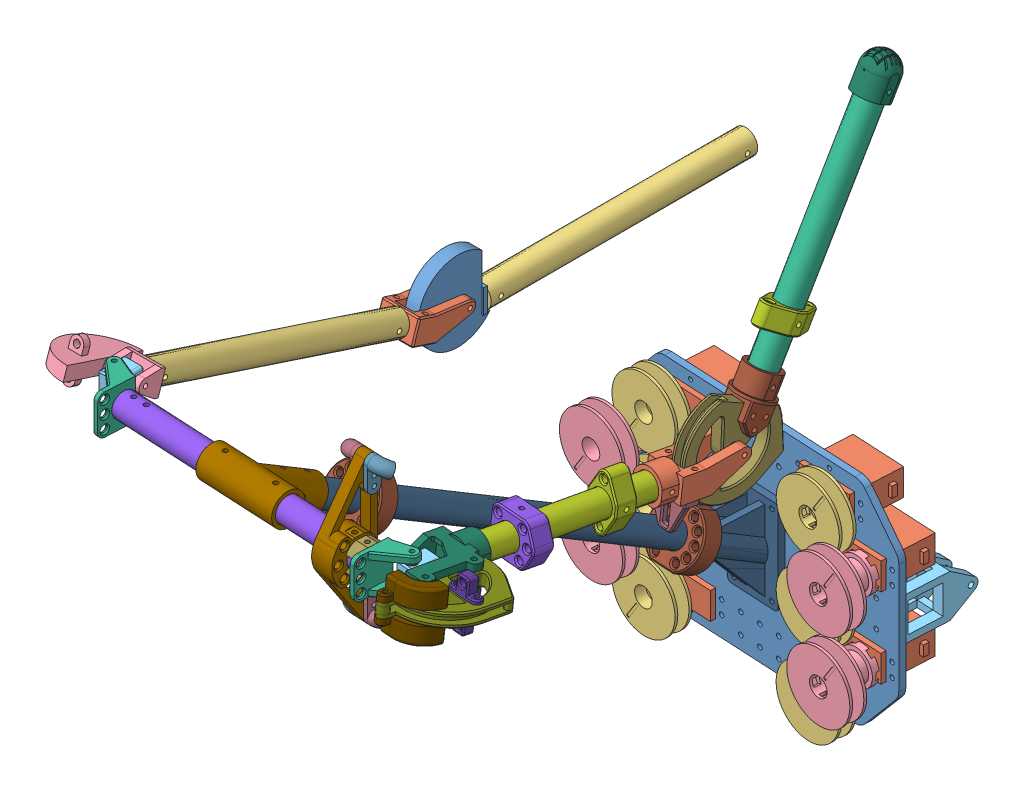
SolidWorks assembly leg, configuration ﾃﾞﾌｫﾙﾄ. Lengths in mm.
Overall size (337.74 498.67 533).
81 component instances, 34 part files, 137 mates.
Components (placement in the parent):
- knee1-1: knee1 [ﾃﾞﾌｫﾙﾄ] at origin size (12.5 60 66)
- knee2-1: knee2 [ﾃﾞﾌｫﾙﾄ] at (0 17.6456 91.0568) x (-1 0 0) z (0 -0.312628 -0.949876) size (28.5 23 60)
- pipe-1: pipe [ﾃﾞﾌｫﾙﾄ] at (0 75.4818 266.7838) x (-1 0 0) z (0 -0.312628 -0.949876) size (18 18 200)
- pipe-2: pipe [ﾃﾞﾌｫﾙﾄ] at (0 0 -185) size (18 18 200)
- shoulder1-1: shoulder1 [ﾃﾞﾌｫﾙﾄ] at (0 70.7924 252.5357) x (1 0 0) z (0 0.312628 0.949876) size (57 30 63)
- shoulder2-1: shoulder2 [ﾃﾞﾌｫﾙﾄ] at (0 79.5426 274.1322) x (1 0 0) z (0 0.000663 1) size (15 15 20)
- shoulder3-2: shoulder3 [ﾃﾞﾌｫﾙﾄ] at (32.4982 79.5596 299.803) x (0 1 -0.000663) z (-0.998699 -0.000034 -0.050986) size (29.5 33 38)
- wire_end_small-1: wire_end_small [ﾃﾞﾌｫﾙﾄ] at (256.2577 129.0444 42.6835) x (-0.071528 0.462872 0.883535) z (-0.03729 -0.886425 0.461367) size (40.5 24.5 15)
- wire_end_5_small-2: wire_end_5_small [ﾃﾞﾌｫﾙﾄ] at (241.707 71.9206 226.8576) x (0.00942 0.993081 -0.117057) z (0.080112 -0.117436 -0.989844) size (31 35.94 15)
- wire_root_curve-1: wire_root_curve [ﾃﾞﾌｫﾙﾄ] at (187.796 79.5649 307.7313) x (0 1 -0.000663) z (0.998699 0.000034 0.050986) size (110 40 16)
- wire_end_small-2: wire_end_small [ﾃﾞﾌｫﾙﾄ] at (246.9143 64.2873 162.5178) x (-0.00942 -0.993081 0.117057) z (-0.080112 0.117436 0.989844) size (40.5 24.5 15)
- connector_45-1: connector_45 [ﾃﾞﾌｫﾙﾄ] at (135.712 -128.1754 -54.6586) x (0.998699 0.000034 0.050986) z (-0.050986 0.000662 0.998699) size (40 70.39 54.3)
- knee-1: knee [ﾃﾞﾌｫﾙﾄ] at (254.5796 89.1552 63.445) x (0.996741 0.000053 0.080664) z (-0.03729 -0.886425 0.461367) size (28.65 93.18 98.72) (flexible)
  - knee_joint_connector-1: knee_joint_connector [outer] at origin size (28.1 28.1 37.95)
  - knee_joint_circle-1: knee_joint_circle [ﾃﾞﾌｫﾙﾄ] at (-4.65 5 31.1808) x (0 1 0) z (1 0 0) size (75 60.98 10)
  - knee2-1: knee2 [outer] at (0.35 53.2056 59.149) x (-1 0 0) z (0 -0.934649 -0.355571) size (28.5 25.58 60)
  - knee_support-1: knee_support [ﾃﾞﾌｫﾙﾄ] at (0.35 28.5085 59.3827) x (-1 0 0) z (0 -0.355571 0.934649) size (28.5 11 23)
  - bearing-1: bearing [ﾃﾞﾌｫﾙﾄ] at (6.1 5 31.1808) x (0 0.527519 -0.849543) z (0 0.849543 0.527519) size (7 5 7)
  - bearing-2: bearing [ﾃﾞﾌｫﾙﾄ] at (-5.4 5 31.1808) x (0 -0.208274 -0.978071) z (0 -0.978071 0.208274) size (7 5 7)
- shoulder-1: shoulder [ﾃﾞﾌｫﾙﾄ] at (238.1019 77.2052 271.4006) x (0.996741 0.000053 0.080664) z (-0.080112 0.117436 0.989844) size (88.08 36.85 85.64) (flexible)
  - shoulder_joint_connector-1: shoulder_joint_connector [outer] at origin size (39.7 24.5 59)
  - shoulder_joint_circle-1: shoulder_joint_circle [ﾃﾞﾌｫﾙﾄ] at (19.95 4.65 26) x (1 0 0) z (0 -1 0) size (40 79.64 10)
  - shoulder_fromknee_middle-2: shoulder_fromknee_middle [ﾃﾞﾌｫﾙﾄ] at (38.95 -5.35 26) x (1 0 0) z (0 1 0) size (24 8 13)
  - shoulder_fromknee_middle-3: shoulder_fromknee_middle [ﾃﾞﾌｫﾙﾄ] at (38.95 4.65 26) x (1 0 0) z (0 -1 0) size (24 8 13)
  - shoulder_fromknee_middle_curve-4: shoulder_fromknee_middle_curve [ﾃﾞﾌｫﾙﾄ] at (18.95 -5.35 58.641) x (0 0 1) z (0 1 0) size (28 28.97 13)
  - shoulder2-1: shoulder2 [ﾃﾞﾌｫﾙﾄ] at (0 0.5839 15.0342) x (1 0 0) z (0 -0.116779 0.993158) size (15 15 20)
  - shoulder3-1: shoulder3 [ﾃﾞﾌｫﾙﾄ] at (-32.7177 -2.3329 39.8407) x (0 -0.993158 -0.116779) z (0.999558 0.003473 -0.029536) size (29.5 33 38)
  - bearing-1: bearing [ﾃﾞﾌｫﾙﾄ] at (-8.25 0 20) x (0 -0.574007 -0.81885) z (0 -0.81885 0.574007) size (7 5 7)
  - bearing-2: bearing [ﾃﾞﾌｫﾙﾄ] at (8.25 0 20) x (0 0.990184 0.139771) z (0 -0.139771 0.990184) size (7 5 7)
  - bearing-3: bearing [ﾃﾞﾌｫﾙﾄ] at (0 -9.3613 28.9682) x (0.861407 0.059314 -0.504441) z (0.507916 -0.100594 0.855513) size (7 5 7)
  - bearing-4: bearing [ﾃﾞﾌｫﾙﾄ] at (0 7.0258 30.895) x (-0.933998 0.041723 -0.354835) z (-0.35728 -0.109071 0.927607) size (7 5 7)
  - shoulder_fromknee_middle_curve-5: shoulder_fromknee_middle_curve [mirror] at (18.95 4.65 58.641) x (0 0 1) z (0 1 0) size (28 28.97 13)
- base_motor-1: base_motor [ﾃﾞﾌｫﾙﾄ] at (111.2544 -128.1829 -65.9202) x (0 1 -0.000663) z (0.998699 0.000034 0.050986) size (192.73 114.3 257.01)
  - base-1: base [ﾃﾞﾌｫﾙﾄ] at origin size (160.1 5 220.2)
  - motor-1: motor [ﾃﾞﾌｫﾙﾄ] at (0 -30 -30.05) x (0 0 1) z (-1 0 0) size (73.36 59.5 70.97)
    - FB5311M-1: FB5311M [ﾃﾞﾌｫﾙﾄ] at origin size (54 44.25 20.1)
    - servo_horn_short-1: servo_horn_short [ﾃﾞﾌｫﾙﾄ] at (-10 42.5 0) x (-0.837169 0 -0.546944) z (0 1 0) size (50 57.04 17)
  - motor-2: motor [ﾃﾞﾌｫﾙﾄ] at (-60 -30 -30.05) x (0 0 1) z (-1 0 0) size (73.36 59.5 70.97)
    - FB5311M-1: FB5311M [ﾃﾞﾌｫﾙﾄ] at origin size (54 44.25 20.1)
    - servo_horn_short-1: servo_horn_short [ﾃﾞﾌｫﾙﾄ] at (-10 42.5 0) x (-0.837169 0 -0.546944) z (0 1 0) size (50 57.04 17)
  - motor-3: motor [ﾃﾞﾌｫﾙﾄ] at (60 -30 -30.05) x (0 0 1) z (-1 0 0) size (73.36 59.5 70.97)
    - FB5311M-1: FB5311M [ﾃﾞﾌｫﾙﾄ] at origin size (54 44.25 20.1)
    - servo_horn_short-1: servo_horn_short [ﾃﾞﾌｫﾙﾄ] at (-10 42.5 0) x (-0.837169 0 -0.546944) z (0 1 0) size (50 57.04 17)
  - motor_long-6: motor_long [ﾃﾞﾌｫﾙﾄ] at (-30 -30 -55.05) x (0 0 1) z (-1 0 0) size (73.92 74.5 73.92) (flexible)
    - FB5311M-1: FB5311M [ﾃﾞﾌｫﾙﾄ] at origin size (54 44.25 20.1)
    - servo_horn_long-1: servo_horn_long [ﾃﾞﾌｫﾙﾄ] at (-10 42.5 0) x (0.789041 0 0.61434) z (0 1 0) size (50 57.04 32)
  - motor_long-5: motor_long [ﾃﾞﾌｫﾙﾄ] at (30 -30 -55.05) x (0 0 1) z (-1 0 0) size (75.45 74.5 73.44)
    - FB5311M-1: FB5311M [ﾃﾞﾌｫﾙﾄ] at origin size (54 44.25 20.1)
    - servo_horn_long-1: servo_horn_long [ﾃﾞﾌｫﾙﾄ] at (-10 42.5 0) x (-0.837169 0 -0.546944) z (0 1 0) size (50 57.04 32)
  - wheel_support-1: wheel_support [ﾃﾞﾌｫﾙﾄ] at (0 0 -67.1) x (0 0 1) z (0 -1 0) size (28.5 32 55)
  - connector_45-1: connector_45 [ﾃﾞﾌｫﾙﾄ] at (0 10 25) x (0 0 1) z (0 1 0) size (40 70.39 54.3)
  - motor-4: motor [ﾃﾞﾌｫﾙﾄ] at (-60 -30 80.05) x (0 0 -1) z (1 0 0) size (73.36 59.5 70.97)
    - FB5311M-1: FB5311M [ﾃﾞﾌｫﾙﾄ] at origin size (54 44.25 20.1)
    - servo_horn_short-1: servo_horn_short [ﾃﾞﾌｫﾙﾄ] at (-10 42.5 0) x (-0.837169 0 -0.546944) z (0 1 0) size (50 57.04 17)
  - motor-5: motor [ﾃﾞﾌｫﾙﾄ] at (0 -30 80.05) x (0 0 -1) z (1 0 0) size (73.36 59.5 70.97)
    - FB5311M-1: FB5311M [ﾃﾞﾌｫﾙﾄ] at origin size (54 44.25 20.1)
    - servo_horn_short-1: servo_horn_short [ﾃﾞﾌｫﾙﾄ] at (-10 42.5 0) x (-0.837169 0 -0.546944) z (0 1 0) size (50 57.04 17)
  - motor-6: motor [ﾃﾞﾌｫﾙﾄ] at (60 -30 80.05) x (0 0 -1) z (1 0 0) size (73.36 59.5 70.97)
    - FB5311M-1: FB5311M [ﾃﾞﾌｫﾙﾄ] at origin size (54 44.25 20.1)
    - servo_horn_short-1: servo_horn_short [ﾃﾞﾌｫﾙﾄ] at (-10 42.5 0) x (-0.837169 0 -0.546944) z (0 1 0) size (50 57.04 17)
  - motor_long-7: motor_long [ﾃﾞﾌｫﾙﾄ] at (-30 -30 105.05) x (0 0 -1) z (1 0 0) size (75.45 74.5 73.44)
    - FB5311M-1: FB5311M [ﾃﾞﾌｫﾙﾄ] at origin size (54 44.25 20.1)
    - servo_horn_long-1: servo_horn_long [ﾃﾞﾌｫﾙﾄ] at (-10 42.5 0) x (-0.837169 0 -0.546944) z (0 1 0) size (50 57.04 32)
  - motor_long-8: motor_long [ﾃﾞﾌｫﾙﾄ] at (30 -30 105.05) x (0 0 -1) z (1 0 0) size (75.45 74.5 73.44)
    - FB5311M-1: FB5311M [ﾃﾞﾌｫﾙﾄ] at origin size (54 44.25 20.1)
    - servo_horn_long-1: servo_horn_long [ﾃﾞﾌｫﾙﾄ] at (-10 42.5 0) x (-0.837169 0 -0.546944) z (0 1 0) size (50 57.04 32)
  - wheel_support-2: wheel_support [ﾃﾞﾌｫﾙﾄ] at (0 0 117.1) x (0 0 -1) z (0 -1 0) size (28.5 32 55)
- pipe_foot-1: pipe_foot [ﾃﾞﾌｫﾙﾄ] at (254.5796 89.1552 63.445) x (-0.996741 -0.000053 -0.080664) z (0.03729 0.886425 -0.461367) size (18 18 190)
- pipe_leg-1: pipe_leg [ﾃﾞﾌｫﾙﾄ] at (238.1019 77.2052 271.4006) x (0.996741 0.000053 0.080664) z (0.080112 -0.117436 -0.989844) size (18 18 150)
- pipe_shoulder-1: pipe_shoulder [ﾃﾞﾌｫﾙﾄ] at (17.5177 79.5591 299.0382) x (0 1 -0.000663) z (0.998699 0.000034 0.050986) size (18 18 200)
- connector_T-2: connector_T [ﾃﾞﾌｫﾙﾄ] at (117.3877 79.5625 304.1368) x (0.044155 -0.500573 -0.864567) z (-0.025493 -0.865694 0.499924) size (62 60 24)
- pipe_body-1: pipe_body [body] at (117.8292 74.5568 295.4912) x (-0.025493 -0.865694 0.499924) z (0.044155 -0.500573 -0.864567) size (18 18 400)
- wire_from_base_mini-1: wire_from_base_mini [ﾃﾞﾌｫﾙﾄ] at (133.5043 -103.1468 -11.4302) x (0.998699 0.000034 0.050986) z (-0.044155 0.500573 0.864567) size (42.5 38.28 15)
- wire_from_base_mini-2: wire_from_base_mini [ﾃﾞﾌｫﾙﾄ] at (121.6928 30.7566 219.8415) x (0.998699 0.000034 0.050986) z (-0.044155 0.500573 0.864567) size (42.5 38.28 15)
- shoulder_patch-1: shoulder_patch [ﾃﾞﾌｫﾙﾄ] at (204.7738 79.5655 308.5981) x (0 1 -0.000663) z (0.998699 0.000034 0.050986) size (23.48 22.98 10)
- wire_root_curve_support-1: wire_root_curve_support [ﾃﾞﾌｫﾙﾄ] at (199.5464 29.5553 293.3448) x (0 1 -0.000663) z (0.998699 0.000034 0.050986) size (25 12.64 15.99)
- wire_root_curve_support_mirror-1: wire_root_curve_support_mirror [ﾃﾞﾌｫﾙﾄ] at (193.5542 129.5551 292.9726) x (0 -1 0.000663) z (-0.998699 -0.000034 -0.050986) size (25 12.64 15.99)
- wire_root_curve_support_mirror-2: wire_root_curve_support_mirror [45] at (191.5568 29.5551 292.937) x (0 1 -0.000663) z (0.998699 0.000034 0.050986) size (25 12.5 15.99)
- wire_root_curve_support-2: wire_root_curve_support [76] at (185.5646 129.5549 292.5647) x (0 -1 0.000663) z (-0.998699 -0.000034 -0.050986) size (25 12.37 15.99)
- foot_simple-1: foot_simple [ﾃﾞﾌｫﾙﾄ] at (261.6647 257.576 -24.2147) x (0.996741 0.000053 0.080664) z (-0.071528 0.462872 0.883535) size (23.48 27.23 24.5)
- wheel-1: wheel [ﾃﾞﾌｫﾙﾄ] at (46.7909 -128.2183 -119.2763) x (0.050879 0.063944 -0.996656) z (0.998699 0.000034 0.050986) size (27.11 27.11 8)
Mates (geometry in assembly coordinates):
- 同心円2: concentric aligned: cylinder of knee2-1 through (0 12.9562 76.8087) axis (0 0.312628 0.949876) radius 6.325; cylinder of pipe-1 through (0 12.9562 76.8087) axis (0 0.312628 0.949876) radius 6.25
- 一致1: coincident anti-aligned: plane of knee2-1 through (0 12.9562 76.8087) normal (0 0.312628 0.949876); plane of pipe-1 through (0 12.9562 76.8087) normal (0 -0.312628 -0.949876)
- 同心円3: concentric aligned: cylinder of knee1-1 through (0 0 15) axis (0 0 -1) radius 6.25; cylinder of pipe-2 through (0 0 15) axis (0 0 -1) radius 6.25
- 一致2: coincident anti-aligned: plane of knee1-1 through (0 0 15) normal (0 0 -1); plane of pipe-2 through (0 0 15) normal (0 0 1)
- 一致3: coincident aligned: plane of knee2-1 through (0 17.6456 91.0568) normal (0 0.949876 -0.312628); plane of pipe-1 through (0 75.4818 266.7838) normal (0 0.949876 -0.312628)
- 一致4: coincident aligned: plane of knee1-1 through (0 0 0) normal (0 1 0); plane of pipe-2 through (0 0 -185) normal (0 1 0)
- 幅2: width anti-aligned: plane of knee2-1 through (-7.25 9 36) normal (1 0 0); plane of knee1-1 through (7.25 9 36) normal (-1 0 0); plane of knee2-1 through (-5 9 36) normal (-1 0 0); plane of knee1-1 through (5 9 36) normal (1 0 0)
- 同心円6: concentric anti-aligned: cylinder of shoulder2-1 through (0 72.0526 289.1372) axis (0 1 -0.000663) radius 2.45; cylinder of shoulder3-2 through (0 69.8026 289.1387) axis (0 -1 0.000663) radius 1.65
- 幅4: width aligned: plane of shoulder3-2 through (0 69.8026 289.1387) normal (0 1 -0.000663); plane of shoulder2-1 through (0 89.3026 289.1257) normal (0 -1 0.000663); plane of shoulder3-2 through (-7.5 72.0559 294.1372) normal (0 -1 0.000663); plane of shoulder2-1 through (-7.5 87.0559 294.1272) normal (0 1 -0.000663)
- 同心円7: concentric aligned: cylinder of shoulder3-2 through (17.5177 79.5591 299.0382) axis (0.998699 0.000034 0.050986) radius 6.45; cylinder of pipe-3 through (17.1329 100.1519 293.0392) axis (0.996076 0.003559 0.08843) radius 6.25
- 一致7: coincident anti-aligned: plane of shoulder3-2 through (17.5177 79.5591 299.0382) normal (0.998699 0.000034 0.050986); plane of pipe-3 through (17.1329 100.1519 293.0392) normal (-0.996076 -0.003559 -0.08843)
- 一致8: coincident anti-aligned: plane of shoulder3-2 through (32.4982 79.5596 299.803) normal (0.050986 -0.000662 -0.998699); plane of pipe-3 through (216.3481 100.8637 310.7252) normal (-0.088502 0.040056 0.99527)
- 同心円8: concentric anti-aligned: cylinder of pipe-4 through (270.6476 122.5449 77.128) axis (-0.154661 -0.093841 0.983501) radius 6.25; cylinder of shoulder1-3 through (228.7413 175.6864 165.6652) axis (-0.138361 -0.342084 -0.929427) radius 6.25
- 同心円9: concentric anti-aligned: cylinder of knee2-2 through (196.4818 175.5319 -79.2352) axis (0.987757 -0.006404 -0.155872) radius 1.65; cylinder of knee1-2 through (228.292 123.8982 -68.5769) axis (-0.99942 0.001398 0.03403) radius 1.65
- 同心円10: concentric aligned: cylinder of shoulder1-3 through (238.9499 180.0829 176.5145) axis (0.9894 -0.005962 -0.145095) radius 1.65; cylinder of shoulder2-2 through (225.1612 174.2633 198.3122) axis (0.987981 -0.006346 -0.154447) radius 2.25
- 一致9: coincident anti-aligned: plane of pipe-4 through (239.7153 103.7767 273.8281) normal (-0.01468 0.995587 0.092686); plane of shoulder1-3 through (226.6659 170.5552 151.7238) normal (0.044094 -0.939651 0.339282)
- 同心円11: concentric aligned: cylinder of pipe-4 through (270.6476 122.5449 77.128) axis (-0.154661 -0.093841 0.983501) radius 6.25; cylinder of knee2-2 through (196.3165 168.6457 -38.2986) axis (0.155994 0.051502 0.986414) radius 6.5
- 同心円12: concentric aligned: cylinder of pipe-5 through (281.7295 136.6436 7.4767) axis (0.159061 0.201035 -0.966584) radius 6.25; cylinder of knee1-2 through (222.6082 133.8129 -88.9826) axis (-0.021318 0.753541 -0.657055) radius 6.25
- 一致10: coincident anti-aligned: plane of pipe-4 through (239.7153 103.7767 273.8281) normal (-0.154661 -0.093841 0.983501); plane of shoulder1-3 through (228.7413 175.6864 165.6652) normal (-0.138361 -0.342084 -0.929427)
- 一致11: coincident anti-aligned: plane of pipe-4 through (270.6476 122.5449 77.128) normal (0.154661 0.093841 -0.983501); plane of knee2-2 through (196.3165 168.6457 -38.2986) normal (0.155994 0.051502 0.986414)
- 一致12: coincident anti-aligned: plane of pipe-5 through (281.7295 136.6436 7.4767) normal (-0.159061 -0.201035 0.966584); plane of knee1-2 through (222.6082 133.8129 -88.9826) normal (-0.021318 0.753541 -0.657055)
- 一致13: coincident aligned: plane of pipe-4 through (239.7153 103.7767 273.8281) normal (-0.01468 0.995587 0.092686); plane of knee2-2 through (198.6564 169.4182 -23.5024) normal (-0.00171 0.998652 -0.05187)
- 幅5: width anti-aligned: plane of knee2-2 through (183.6409 175.6151 -77.2088) normal (0.987757 -0.006404 -0.155872); plane of knee1-2 through (196.4818 175.5319 -79.2352) normal (-0.987757 0.006404 0.155872); plane of knee2-2 through (218.2978 123.9121 -68.2366) normal (-0.99942 0.001398 0.03403); plane of knee1-2 through (228.292 123.8982 -68.5769) normal (0.99942 -0.001398 -0.03403)
- 幅6: width anti-aligned: plane of shoulder1-3 through (238.9499 180.0829 176.5145) normal (-0.9894 0.005962 0.145095); plane of shoulder2-2 through (222.1301 180.1842 178.9811) normal (0.9894 -0.005962 -0.145095); plane of shoulder1-3 through (242.2996 182.2702 210.4948) normal (0.987981 -0.006346 -0.154447); plane of shoulder2-2 through (227.4799 182.3654 212.8115) normal (-0.987981 0.006346 0.154447)
- 一致14: coincident aligned: plane of pipe-5 through (313.5418 176.8507 -185.8401) normal (0.031919 0.977489 0.208556); plane of knee1-2 through (222.2884 145.116 -98.8384) normal (0.026562 0.6574 0.753074)
- 同心円13: concentric anti-aligned: cylinder of pipe-3 through (17.1329 100.1519 293.0392) axis (0.996076 0.003559 0.08843) radius 6.25; cylinder of shoulder3-3 through (217.3952 175.081 218.2134) axis (-0.992021 0.005176 0.125969) radius 6.25
- 一致15: coincident anti-aligned: plane of pipe-3 through (216.3481 100.8637 310.7252) normal (-0.088502 0.040056 0.99527); plane of shoulder3-3 through (202.5149 175.1586 220.103) normal (-0.126075 -0.040725 -0.991184)
- 一致16: coincident anti-aligned: plane of pipe-3 through (216.3481 100.8637 310.7252) normal (0.996076 0.003559 0.08843); plane of shoulder3-3 through (217.3952 175.081 218.2134) normal (-0.992021 0.005176 0.125969)
- 同心円14: concentric aligned: cylinder of shoulder2-2 through (234.1169 167.1276 207.3332) axis (0 0.999157 -0.041052) radius 2.25; cylinder of shoulder3-3 through (234.1169 184.3631 206.6251) axis (0 0.999157 -0.041052) radius 1.65
- 幅7: width anti-aligned: plane of shoulder3-3 through (234.1169 184.3631 206.6251) normal (0 -0.999157 0.041052); plane of shoulder2-2 through (234.1169 164.8795 207.4256) normal (0 0.999157 -0.041052); plane of shoulder3-3 through (227.4799 182.3654 212.8115) normal (0 0.999157 -0.041052); plane of shoulder2-2 through (227.4799 167.378 213.4273) normal (0 -0.999157 0.041052)
- 同心円15: concentric anti-aligned: cylinder of knee1-1 through (5 9 36) axis (-1 0 0) radius 1.65; cylinder of knee2-1 through (7.25 9 36) axis (1 0 0) radius 1.65
- 同心円16: concentric anti-aligned: cylinder of pipe-1 through (0 12.9562 76.8087) axis (0 0.312628 0.949876) radius 6.25; cylinder of shoulder1-1 through (0 75.4818 266.7838) axis (0 -0.312628 -0.949876) radius 6.25
- 同心円17: concentric anti-aligned: cylinder of shoulder1-1 through (-8.5 79.5459 279.1322) axis (-1 0 0) radius 1.65; cylinder of shoulder2-1 through (-7.5 79.5459 279.1322) axis (1 0 0) radius 2.45
- 一致17: coincident anti-aligned: plane of pipe-1 through (0 75.4818 266.7838) normal (0 0.312628 0.949876); plane of shoulder1-1 through (0 75.4818 266.7838) normal (0 -0.312628 -0.949876)
- 幅8: width anti-aligned: plane of shoulder1-1 through (-8.5 79.5459 279.1322) normal (1 0 0); plane of shoulder2-1 through (8.5 79.5459 279.1322) normal (-1 0 0); plane of shoulder1-1 through (-7.5 87.0559 294.1272) normal (-1 0 0); plane of shoulder2-1 through (7.5 87.0559 294.1272) normal (1 0 0)
- 一致18: coincident aligned: plane of pipe-1 through (0 75.4818 266.7838) normal (0 0.949876 -0.312628); plane of shoulder1-1 through (0 70.7924 252.5357) normal (0 0.949876 -0.312628)
- 同心円21: concentric anti-aligned: cylinder of pipe-3 through (17.1329 100.1519 293.0392) axis (0.996076 0.003559 0.08843) radius 9; cylinder of wire_root_curve-1 through (195.7856 79.5652 308.1392) axis (-0.998699 -0.000034 -0.050986) radius 9.25
- 同心円22: concentric aligned: cylinder of pipe-3 through (17.1329 100.1519 293.0392) axis (0.996076 0.003559 0.08843) radius 9; cylinder of connector_T-1 through (86.8582 100.4011 299.2293) axis (0.996076 0.003559 0.08843) radius 9.25
- 同心円23: concentric anti-aligned: cylinder of connector_T-1 through (115.8191 108.7078 311.9303) axis (0.070862 -0.630668 -0.77281) radius 9.25; cylinder of pipe-6 through (136.2448 -134.2161 -65.0917) axis (-0.044155 0.500573 0.864567) radius 9
- 正接1: tangent anti-aligned: cylinder of connector_T-1 through (86.8582 100.4011 299.2293) axis (0.996076 0.003559 0.08843) radius 13; plane of pipe-6 through (118.5828 66.0133 280.7352) normal (-0.044155 0.500573 0.864567)
- 同心円25: concentric aligned: cylinder of pipe-6 through (136.2448 -134.2161 -65.0917) axis (-0.044155 0.500573 0.864567) radius 9; cylinder of wire_all-1 through (123.3985 11.4189 186.4422) axis (-0.044155 0.500573 0.864567) radius 9
- 同心円26: concentric aligned: cylinder of pipe-6 through (136.2448 -134.2161 -65.0917) axis (-0.044155 0.500573 0.864567) radius 9; cylinder of connector_45-1 through (136.6759 -139.103 -73.5322) axis (-0.044155 0.500573 0.864567) radius 9.4
- 一致23: coincident aligned: plane of pipe-6 through (118.5828 66.0133 280.7352) normal (0.982784 -0.133648 0.127573); plane of connector_45-1 through (135.712 -128.1754 -54.6586) normal (0.998699 0.000034 0.050986)
- 一致24: coincident anti-aligned: plane of connector_T-1 through (116.7405 100.5078 301.8822) normal (-0.996076 -0.003559 -0.08843); plane of pipe-6 through (118.5828 66.0133 280.7352) normal (0.982784 -0.133648 0.127573)
- 一致25: coincident anti-aligned: plane of connector_45-1 through (135.9669 -128.1788 -59.6521) normal (0.050986 -0.000662 -0.998699); plane of plate-1 through (65.1542 -294.6616 162.0898) normal (-0.119372 0.848521 -0.515521)
- 同心円27: concentric aligned: cylinder of connector_45-1 through (118.2178 -98.1433 -6.2051) axis (0.050986 -0.000662 -0.998699) radius 1.75; cylinder of plate-1 through (85.9891 -278.9347 183.151) axis (0.119372 -0.848521 0.515521) radius 1.75
- 同心円28: concentric aligned: cylinder of connector_45-1 through (118.2178 -158.1433 -6.1654) axis (0.050986 -0.000662 -0.998699) radius 1.75; cylinder of plate-1 through (73.4361 -310.6791 133.8082) axis (0.119372 -0.848521 0.515521) radius 1.75
- 同心円29: concentric aligned: cylinder of pipe-6 through (136.2448 -134.2161 -65.0917) axis (-0.044155 0.500573 0.864567) radius 9; cylinder of wire_all-2 through (130.6166 -70.4106 45.1102) axis (-0.044155 0.500573 0.864567) radius 9
- 同心円30: concentric aligned: cylinder of pipe-5 through (281.7295 136.6436 7.4767) axis (0.159061 0.201035 -0.966584) radius 9; cylinder of wire_end_small-1 through (255.978 122.3962 46.1438) axis (0.03729 0.886425 -0.461367) radius 9.25
- 一致26: coincident anti-aligned: plane of pipe-5 through (313.5418 176.8507 -185.8401) normal (0.986753 -0.064026 0.149064); plane of wire_end_small-1 through (256.2577 129.0444 42.6835) normal (-0.996741 -0.000053 -0.080664)
- 同心円31: concentric anti-aligned: cylinder of pipe-4 through (270.6476 122.5449 77.128) axis (-0.154661 -0.093841 0.983501) radius 9; cylinder of wire_end_small-2 through (246.3135 65.1681 169.9416) axis (0.080112 -0.117436 -0.989844) radius 9.25
- 一致27: coincident anti-aligned: plane of pipe-4 through (239.7153 103.7767 273.8281) normal (-0.987858 -0.000103 -0.155356); plane of wire_end_small-2 through (246.9143 64.2873 162.5178) normal (0.996741 0.000053 0.080664)
- 同心円32: concentric aligned: cylinder of pipe-4 through (270.6476 122.5449 77.128) axis (-0.154661 -0.093841 0.983501) radius 9; cylinder of wire_end_5_small-2 through (242.3079 71.0399 219.4338) axis (-0.080112 0.117436 0.989844) radius 9.25
- 一致28: coincident aligned: plane of pipe-4 through (239.7153 103.7767 273.8281) normal (-0.01468 0.995587 0.092686); plane of wire_end_5_small-2 through (241.707 71.9206 226.8576) normal (0.00942 0.993081 -0.117057)
- 幅9: width anti-aligned: plane of knee2-2 through (183.6409 175.6151 -77.2088) normal (0.987757 -0.006404 -0.155872); plane of knee-1/knee_joint_circle-1 through (196.4818 175.5319 -79.2352) normal (-0.987757 0.006404 0.155872); plane of knee2-2 through (248.4244 63.8299 81.8734) normal (-0.996741 -0.000053 -0.080664); plane of knee-1/knee_joint_circle-1 through (258.3918 63.8305 82.6801) normal (0.996741 0.000053 0.080664)
- 同心円35: concentric aligned: cylinder of pipe-4 through (270.6476 122.5449 77.128) axis (-0.154661 -0.093841 0.983501) radius 6.25; cylinder of shoulder-1/shoulder_joint_connector-1 through (237.7483 62.0339 260.918) axis (-0.044155 0.500573 0.864567) radius 6.325
- 一致31: coincident anti-aligned: plane of pipe-4 through (239.7153 103.7767 273.8281) normal (-0.154661 -0.093841 0.983501); plane of shoulder-1/shoulder_joint_connector-1 through (238.1019 77.2052 271.4006) normal (0.080112 -0.117436 -0.989844)
- 同心円36: concentric aligned: cylinder of shoulder2-2 through (225.1612 174.2633 198.3122) axis (0.987981 -0.006346 -0.154447) radius 2.25; cylinder of shoulder-1/shoulder_joint_connector-1 through (246.2179 79.5545 291.9839) axis (0.996741 0.000053 0.080664) radius 1.65
- 平行1: parallel anti-aligned: plane of pipe-4 through (239.7153 103.7767 273.8281) normal (-0.01468 0.995587 0.092686); plane of shoulder-1/shoulder_joint_circle-1 through (255.9478 84.8774 298.2015) normal (-0.00942 -0.993081 0.117057)
- 幅10: width anti-aligned: plane of shoulder-1/shoulder_joint_connector-1 through (247.8202 77.2057 272.1871) normal (-0.996741 -0.000053 -0.080664); plane of shoulder2-2 through (218.1836 135.3588 202.3528) normal (0.989315 -0.033774 -0.141829); plane of shoulder-1/shoulder_joint_connector-1 through (242.2996 182.2702 210.4948) normal (0.987981 -0.006346 -0.154447); plane of shoulder2-2 through (227.4799 182.3654 212.8115) normal (-0.987981 0.006346 0.154447)
- 同心円37: concentric aligned: cylinder of knee2-2 through (185.7003 159.3067 -44.2423) axis (-0.00171 0.998652 -0.05187) radius 1.75; cylinder of knee_support-1 through (185.7054 156.3107 -44.0867) axis (-0.00171 0.998652 -0.05187) radius 1.75
- 同心円38: concentric aligned: cylinder of knee2-2 through (204.4676 159.185 -47.2039) axis (-0.00171 0.998652 -0.05187) radius 1.75; cylinder of knee_support-1 through (204.4728 156.189 -47.0483) axis (-0.00171 0.998652 -0.05187) radius 1.75
- 一致32: coincident anti-aligned: plane of knee2-2 through (208.2109 159.4233 -42.7394) normal (0.00171 -0.998652 0.05187); plane of knee_support-1 through (195.084 159.2458 -45.7231) normal (-0.00171 0.998652 -0.05187)
- 同心円39: concentric: cylinder of pipe-5 through (185.2479 180.0429 -108.9085) axis (-0.146891 0.298304 -0.9431) radius 6.25; cylinder of knee-1/Assem1^knee-1/knee_joint_connector-1 through (183.0445 184.5175 -123.055) axis (0.146891 -0.298304 0.9431) radius 6.75
- 一致33: coincident: plane of pipe-5 through (185.2479 180.0429 -108.9085) normal (0.146891 -0.298304 0.9431); plane of knee-1/Assem1^knee-1/knee_joint_connector-1 through (185.2479 180.0429 -108.9085) normal (-0.146891 0.298304 -0.9431)
- 同心円40: concentric: cylinder of knee2-2 through (196.4818 175.5319 -79.2352) axis (0.987757 -0.006404 -0.155872) radius 1.65; cylinder of knee-1/Assem1^knee-1/knee_joint_circle-1 through (195.0001 175.5415 -79.0014) axis (-0.987757 0.006404 0.155872) radius 2.25
- 幅11: width: plane of knee2-2 through (183.6409 175.6151 -77.2088) normal (0.987757 -0.006404 -0.155872); plane of knee-1/Assem1^knee-1/knee_joint_circle-1 through (196.4818 175.5319 -79.2352) normal (-0.987757 0.006404 0.155872); plane of knee2-2 through (185.1226 175.6055 -77.4427) normal (-0.987757 0.006404 0.155872); plane of knee-1/Assem1^knee-1/knee_joint_circle-1 through (195.0001 175.5415 -79.0014) normal (0.987757 -0.006404 -0.155872)
- 同心円41: concentric anti-aligned: cylinder of pipe-5 through (281.7295 136.6436 7.4767) axis (0.159061 0.201035 -0.966584) radius 9; cylinder of knee-1/knee_joint_connector-1 through (247.6677 -27.845 59.8145) axis (-0.050678 0.110443 0.99259) radius 6.325
- 一致34: coincident anti-aligned: plane of pipe-5 through (281.7295 136.6436 7.4767) normal (-0.159061 -0.201035 0.966584); plane of knee-1/knee_joint_connector-1 through (254.5796 89.1552 63.445) normal (0.03729 0.886425 -0.461367)
- 同心円42: concentric aligned: cylinder of pipe-4 through (270.6476 122.5449 77.128) axis (-0.154661 -0.093841 0.983501) radius 6.25; cylinder of knee-1/knee2-1 through (243.7093 -5.5436 144.2014) axis (-0.044155 0.500573 0.864567) radius 6.325
- 一致35: coincident anti-aligned: plane of pipe-4 through (270.6476 122.5449 77.128) normal (0.154661 0.093841 -0.983501); plane of knee-1/knee2-1 through (250.1188 59.5899 122.924) normal (-0.080112 0.117436 0.989844)
- 一致36: coincident: plane of pipe-4 through (225.0662 136.8995 181.2502) normal (-0.989315 0.033774 0.141829); plane of knee-1 through (189.6272 188.6981 -78.2867) normal (0.989315 -0.033774 -0.141829)
- 同心円43: concentric anti-aligned: cylinder of pipe-3 through (17.1329 100.1519 293.0392) axis (0.996076 0.003559 0.08843) radius 6.25; cylinder of shoulder-1/shoulder3-1 through (217.2576 79.5659 309.2354) axis (-0.998699 -0.000034 -0.050986) radius 6.45
- 一致37: coincident anti-aligned: plane of pipe-3 through (216.3481 100.8637 310.7252) normal (0.996076 0.003559 0.08843); plane of shoulder-1/shoulder3-1 through (217.2576 79.5659 309.2354) normal (-0.998699 -0.000034 -0.050986)
- 同心円44: concentric aligned: cylinder of pipe-5 through (274.0417 138.7276 -1.1143) axis (0.986753 -0.064026 0.149064) radius 1.75; cylinder of knee-1/knee_joint_connector-1 through (236.9511 -27.017 66.7313) axis (0.998699 0.000034 0.050986) radius 1.65
- 幅12: width aligned: plane of pipe-3 through (216.3481 100.8637 310.7252) normal (0.996076 0.003559 0.08843); plane of pipe-3 through (17.1329 100.1519 293.0392) normal (-0.996076 -0.003559 -0.08843); plane of connector_T-1 through (146.6227 100.6146 304.5351) normal (0.996076 0.003559 0.08843); plane of connector_T-1 through (86.8582 100.4011 299.2293) normal (-0.996076 -0.003559 -0.08843)
- 同心円45: concentric anti-aligned: cylinder of connector_45-1 through (148.1788 -158.1423 -4.6358) axis (0.050986 -0.000662 -0.998699) radius 1.75; cylinder of base_motor-1/base-1 through (151.2024 -158.1816 -63.8609) axis (-0.050986 0.000662 0.998699) radius 1.75
- 同心円46: concentric anti-aligned: cylinder of connector_45-1 through (118.2178 -158.1433 -6.1654) axis (0.050986 -0.000662 -0.998699) radius 1.75; cylinder of base_motor-1/base-1 through (121.2414 -158.1826 -65.3905) axis (-0.050986 0.000662 0.998699) radius 1.75
- 一致38: coincident anti-aligned: plane of connector_45-1 through (135.9669 -128.1788 -59.6521) normal (0.050986 -0.000662 -0.998699); plane of base_motor-1/base-1 through (160.9344 -128.1779 -58.3774) normal (-0.050986 0.000662 0.998699)
- 同心円47: concentric aligned: cylinder of knee-1/knee_joint_connector-1 through (247.6677 -27.845 59.8145) axis (-0.050678 0.110443 0.99259) radius 6.325; cylinder of pipe_foot-1 through (256.5363 -47.1725 -113.8886) axis (-0.050678 0.110443 0.99259) radius 6.25
- 同心円48: concentric anti-aligned: cylinder of knee-1/knee_joint_connector-1 through (236.9511 -27.017 66.7313) axis (0.998699 0.000034 0.050986) radius 1.65; cylinder of pipe_foot-1 through (256.2759 -27.0164 67.7178) axis (-0.998699 -0.000034 -0.050986) radius 1.75
- 同心円49: concentric anti-aligned: cylinder of wire_end_small-1 through (255.978 122.3962 46.1438) axis (0.03729 0.886425 -0.461367) radius 9.25; cylinder of pipe_foot-1 through (261.6647 257.576 -24.2147) axis (-0.03729 -0.886425 0.461367) radius 9
- 同心円50: concentric aligned: cylinder of wire_end_small-1 through (268.4677 129.045 43.6717) axis (-0.996741 -0.000053 -0.080664) radius 1.75; cylinder of pipe_foot-1 through (265.2283 129.0448 43.4095) axis (-0.996741 -0.000053 -0.080664) radius 1.75
- 同心円51: concentric aligned: cylinder of shoulder-1/shoulder_joint_connector-1 through (237.7483 62.0339 260.918) axis (-0.044155 0.500573 0.864567) radius 6.325; cylinder of pipe_leg-1 through (243.7093 -5.5436 144.2014) axis (-0.044155 0.500573 0.864567) radius 6.25
- 同心円52: concentric aligned: cylinder of shoulder-1/shoulder_joint_connector-1 through (222.6864 65.7877 266.6502) axis (0.998699 0.000034 0.050986) radius 1.65; cylinder of pipe_leg-1 through (228.4289 65.7878 266.9434) axis (0.998699 0.000034 0.050986) radius 1.75
- 同心円53: concentric aligned: cylinder of wire_end_5_small-2 through (242.3079 71.0399 219.4338) axis (-0.080112 0.117436 0.989844) radius 9.25; cylinder of pipe_leg-1 through (250.1188 59.5899 122.924) axis (-0.080112 0.117436 0.989844) radius 9
- 同心円54: concentric anti-aligned: cylinder of wire_end_5_small-2 through (241.561 56.5279 228.672) axis (0.00942 0.993081 -0.117057) radius 1.75; cylinder of pipe_leg-1 through (241.7918 80.8583 225.8041) axis (-0.00942 -0.993081 0.117057) radius 1.75
- 同心円55: concentric anti-aligned: cylinder of wire_end_small-2 through (246.3135 65.1681 169.9416) axis (0.080112 -0.117436 -0.989844) radius 9.25; cylinder of pipe_leg-1 through (250.1188 59.5899 122.924) axis (-0.080112 0.117436 0.989844) radius 9
- 同心円56: concentric aligned: cylinder of wire_end_small-2 through (234.7042 64.2867 161.5296) axis (0.996741 0.000053 0.080664) radius 1.75; cylinder of pipe_leg-1 through (237.9436 64.2868 161.7918) axis (0.996741 0.000053 0.080664) radius 1.75
- 同心円57: concentric aligned: cylinder of knee-1/knee2-1 through (243.7093 -5.5436 144.2014) axis (-0.044155 0.500573 0.864567) radius 6.325; cylinder of pipe_leg-1 through (243.7093 -5.5436 144.2014) axis (-0.044155 0.500573 0.864567) radius 6.25
- 同心円58: concentric anti-aligned: cylinder of knee-1/knee2-1 through (257.6096 -1.7888 151.4122) axis (-0.998699 -0.000034 -0.050986) radius 1.65; cylinder of pipe_leg-1 through (234.3898 -1.7896 150.2268) axis (0.998699 0.000034 0.050986) radius 1.75
- 同心円59: concentric aligned: cylinder of shoulder-1/shoulder3-1 through (217.2576 79.5659 309.2354) axis (-0.998699 -0.000034 -0.050986) radius 6.45; cylinder of pipe_shoulder-1 through (217.2576 79.5659 309.2354) axis (-0.998699 -0.000034 -0.050986) radius 6.25
- 同心円60: concentric anti-aligned: cylinder of shoulder-1/shoulder3-1 through (209.7673 94.3156 308.8432) axis (0 -1 0.000663) radius 1.65; cylinder of pipe_shoulder-1 through (209.7673 70.5656 308.859) axis (0 1 -0.000663) radius 1.75
- 同心円61: concentric aligned: cylinder of wire_root_curve-1 through (199.7804 24.5653 308.3796) axis (0 1 -0.000663) radius 1.75; cylinder of pipe_shoulder-1 through (199.7804 70.5653 308.3491) axis (0 1 -0.000663) radius 1.75
- 同心円62: concentric aligned: cylinder of wire_root_curve-1 through (195.7856 79.5652 308.1392) axis (-0.998699 -0.000034 -0.050986) radius 9.25; cylinder of pipe_shoulder-1 through (217.2576 79.5659 309.2354) axis (-0.998699 -0.000034 -0.050986) radius 9
- 同心円63: concentric aligned: cylinder of shoulder3-2 through (25.008 64.8094 299.4304) axis (0 1 -0.000663) radius 1.65; cylinder of pipe_shoulder-1 through (25.008 70.5594 299.4266) axis (0 1 -0.000663) radius 1.75
- 同心円64: concentric anti-aligned: cylinder of shoulder3-2 through (17.5177 79.5591 299.0382) axis (0.998699 0.000034 0.050986) radius 6.45; cylinder of pipe_shoulder-1 through (217.2576 79.5659 309.2354) axis (-0.998699 -0.000034 -0.050986) radius 6.25
- 同心円65: concentric aligned: cylinder of pipe_shoulder-1 through (217.2576 79.5659 309.2354) axis (-0.998699 -0.000034 -0.050986) radius 9; cylinder of connector_T-2 through (147.3486 79.5635 305.6664) axis (-0.998699 -0.000034 -0.050986) radius 9.25
- 同心円66: concentric anti-aligned: cylinder of pipe_shoulder-1 through (137.3616 70.5632 305.1625) axis (0 1 -0.000663) radius 1.75; cylinder of connector_T-2 through (137.3616 95.9555 305.1457) axis (0 -1 0.000663) radius 1.75
- 同心円67: concentric anti-aligned: cylinder of pipe-6 through (136.2448 -134.2161 -65.0917) axis (-0.044155 0.500573 0.864567) radius 9; cylinder of connector_T-2 through (116.8577 85.5704 314.5134) axis (0.044155 -0.500573 -0.864567) radius 9.25
- 同心円68: concentric anti-aligned: cylinder of connector_T-2 through (116.8577 85.5704 314.5134) axis (0.044155 -0.500573 -0.864567) radius 9.25; cylinder of pipe_body-1 through (135.4912 -125.6726 -50.3358) axis (-0.044155 0.500573 0.864567) radius 6.25
- 同心円69: concentric aligned: cylinder of connector_T-2 through (118.5767 79.9394 280.8464) axis (-0.025493 -0.865694 0.499924) radius 1.75; cylinder of pipe_body-1 through (118.5002 77.3423 282.3462) axis (-0.025493 -0.865694 0.499924) radius 1.75
- 同心円70: concentric aligned: cylinder of connector_45-1 through (136.6759 -139.103 -73.5322) axis (-0.044155 0.500573 0.864567) radius 9.4; cylinder of pipe_body-1 through (135.4912 -125.6726 -50.3358) axis (-0.044155 0.500573 0.864567) radius 9
- 同心円71: concentric aligned: cylinder of wire_all-2 through (130.6166 -70.4106 45.1102) axis (-0.044155 0.500573 0.864567) radius 9; cylinder of pipe_body-1 through (135.4912 -125.6726 -50.3358) axis (-0.044155 0.500573 0.864567) radius 9
- 同心円72: concentric aligned: cylinder of wire_all-1 through (123.3985 11.4189 186.4422) axis (-0.044155 0.500573 0.864567) radius 9; cylinder of pipe_body-1 through (135.4912 -125.6726 -50.3358) axis (-0.044155 0.500573 0.864567) radius 9
- 同心円73: concentric aligned: cylinder of pipe_body-1 through (135.4912 -125.6726 -50.3358) axis (-0.044155 0.500573 0.864567) radius 9; cylinder of wire_from_base-1 through (132.309 -89.5965 11.9732) axis (-0.044155 0.500573 0.864567) radius 9.25
- 同心円74: concentric anti-aligned: cylinder of pipe_body-1 through (135.4912 -125.6726 -50.3358) axis (-0.044155 0.500573 0.864567) radius 9; cylinder of wire_from_base_mini-1 through (132.8419 -95.6382 1.5383) axis (0.044155 -0.500573 -0.864567) radius 9.25
- 同心円75: concentric anti-aligned: cylinder of connector_45-1 through (132.5446 -155.7336 7.4014) axis (0.025493 0.865694 -0.499924) radius 1.75; cylinder of pipe_body-1 through (134.1752 -100.3613 -24.5752) axis (-0.025493 -0.865694 0.499924) radius 1.75
- 同心円76: concentric anti-aligned: cylinder of pipe_body-1 through (133.4025 -91.6012 -9.4453) axis (-0.025493 -0.865694 0.499924) radius 1.75; cylinder of wire_from_base_mini-1 through (132.6852 -115.9618 4.6225) axis (0.025493 0.865694 -0.499924) radius 1.75
- 同心円77: concentric anti-aligned: cylinder of pipe_body-1 through (135.4912 -125.6726 -50.3358) axis (-0.044155 0.500573 0.864567) radius 9; cylinder of wire_from_base_mini-2 through (121.0304 38.2652 232.81) axis (0.044155 -0.500573 -0.864567) radius 9.25
- 同心円78: concentric anti-aligned: cylinder of pipe_body-1 through (121.591 42.3022 221.8265) axis (-0.025493 -0.865694 0.499924) radius 1.75; cylinder of wire_from_base_mini-2 through (120.8737 17.9416 235.8943) axis (0.025493 0.865694 -0.499924) radius 1.75
- 平行2: parallel aligned: plane of wire_root-1 through (188.5607 129.555 292.7177) normal (-0.998699 -0.000034 -0.050986); plane of shoulder-1/shoulder2-1
- 平行3: parallel aligned: cylinder of pipe_leg-1 through (243.7093 -5.5436 144.2014) axis (-0.044155 0.500573 0.864567) radius 9; cylinder of pipe_body-1 through (135.4912 -125.6726 -50.3358) axis (-0.044155 0.500573 0.864567) radius 9
- 同心円79: concentric anti-aligned: cylinder of knee-1/knee_joint_connector-1 through (240.8551 95.8027 58.8515) axis (0.996741 0.000053 0.080664) radius 1.65; cylinder of pipe_foot-1 through (263.83 95.8039 60.7108) axis (-0.996741 -0.000053 -0.080664) radius 1.75
- 同心円80: concentric aligned: cylinder of knee-1/knee_joint_connector-1 through (255.139 102.4516 56.5245) axis (-0.03729 -0.886425 0.461367) radius 9.25; cylinder of pipe_foot-1 through (261.6647 257.576 -24.2147) axis (-0.03729 -0.886425 0.461367) radius 9
- 同心円81: concentric anti-aligned: cylinder of knee-1/knee2-1 through (263.7215 60.4714 131.4973) axis (-0.996741 -0.000053 -0.080664) radius 1.65; cylinder of pipe_leg-1 through (240.5473 60.4702 129.6219) axis (0.996741 0.000053 0.080664) radius 1.75
- 同心円82: concentric anti-aligned: cylinder of knee-1/knee2-1 through (248.9171 61.3514 137.7717) axis (0.080112 -0.117436 -0.989844) radius 9.25; cylinder of pipe_leg-1 through (250.1188 59.5899 122.924) axis (-0.080112 0.117436 0.989844) radius 9
- 同心円83: concentric aligned: cylinder of shoulder-1/shoulder_joint_connector-1 through (224.0009 76.3237 262.787) axis (0.996741 0.000053 0.080664) radius 1.65; cylinder of pipe_leg-1 through (229.7321 76.324 263.2508) axis (0.996741 0.000053 0.080664) radius 1.75
- 同心円84: concentric aligned: cylinder of shoulder-1/shoulder_joint_connector-1 through (239.3036 75.4437 256.5529) axis (-0.080112 0.117436 0.989844) radius 9.25; cylinder of pipe_leg-1 through (250.1188 59.5899 122.924) axis (-0.080112 0.117436 0.989844) radius 9
- 同心円85: concentric aligned: cylinder of pipe_shoulder-1 through (217.2576 79.5659 309.2354) axis (-0.998699 -0.000034 -0.050986) radius 9; cylinder of shoulder_patch-1 through (214.7608 79.5658 309.108) axis (-0.998699 -0.000034 -0.050986) radius 9.25
- 同心円86: concentric aligned: cylinder of pipe_shoulder-1 through (209.7673 70.5656 308.859) axis (0 1 -0.000663) radius 1.75; cylinder of shoulder_patch-1 through (209.7673 67.8263 308.8608) axis (0 1 -0.000663) radius 1.65
- 一致39: coincident anti-aligned: plane of wire_root_curve-1 through (196.5503 129.5552 293.1256) normal (0.998699 0.000034 0.050986); plane of wire_root_curve_support-1 through (196.5503 29.5552 293.1919) normal (-0.998699 -0.000034 -0.050986)
- 同心円87: concentric aligned: cylinder of wire_root_curve-1 through (188.5607 37.555 292.7787) axis (0.998699 0.000034 0.050986) radius 1.65; cylinder of wire_root_curve_support-1 through (196.5503 37.5552 293.1866) axis (0.998699 0.000034 0.050986) radius 1.65
- 同心円88: concentric aligned: cylinder of wire_root_curve-1 through (188.5607 44.555 292.7741) axis (0.998699 0.000034 0.050986) radius 1.65; cylinder of wire_root_curve_support-1 through (196.5503 44.5552 293.1819) axis (0.998699 0.000034 0.050986) radius 1.65
- 同心円89: concentric aligned: cylinder of wire_root_curve-1 through (188.5607 121.555 292.723) axis (0.998699 0.000034 0.050986) radius 1.65; cylinder of wire_root_curve_support_mirror-1 through (196.5503 121.5552 293.1309) axis (0.998699 0.000034 0.050986) radius 1.65
- 同心円90: concentric aligned: cylinder of wire_root_curve-1 through (188.5607 114.555 292.7276) axis (0.998699 0.000034 0.050986) radius 1.65; cylinder of wire_root_curve_support_mirror-1 through (196.5503 114.5552 293.1355) axis (0.998699 0.000034 0.050986) radius 1.65
- 一致40: coincident anti-aligned: plane of wire_root_curve-1 through (196.5503 129.5552 293.1256) normal (0.998699 0.000034 0.050986); plane of wire_root_curve_support_mirror-1 through (196.5503 129.5552 293.1256) normal (-0.998699 -0.000034 -0.050986)
- 一致41: coincident anti-aligned: plane of wire_root_curve-1 through (188.5607 129.555 292.7177) normal (-0.998699 -0.000034 -0.050986); plane of wire_root_curve_support_mirror-2 through (188.5607 29.555 292.784) normal (0.998699 0.000034 0.050986)
- 同心円91: concentric anti-aligned: cylinder of wire_root_curve-1 through (188.5607 37.555 292.7787) axis (0.998699 0.000034 0.050986) radius 1.65; cylinder of wire_root_curve_support_mirror-2 through (188.5607 37.555 292.7787) axis (-0.998699 -0.000034 -0.050986) radius 1.65
- 同心円92: concentric anti-aligned: cylinder of wire_root_curve-1 through (188.5607 44.555 292.7741) axis (0.998699 0.000034 0.050986) radius 1.65; cylinder of wire_root_curve_support_mirror-2 through (188.5607 44.555 292.7741) axis (-0.998699 -0.000034 -0.050986) radius 1.65
- 同心円93: concentric anti-aligned: cylinder of wire_root_curve-1 through (188.5607 121.555 292.723) axis (0.998699 0.000034 0.050986) radius 1.65; cylinder of wire_root_curve_support-2 through (188.5607 121.555 292.723) axis (-0.998699 -0.000034 -0.050986) radius 1.65
- 同心円94: concentric anti-aligned: cylinder of wire_root_curve-1 through (188.5607 114.555 292.7276) axis (0.998699 0.000034 0.050986) radius 1.65; cylinder of wire_root_curve_support-2 through (188.5607 114.555 292.7276) axis (-0.998699 -0.000034 -0.050986) radius 1.65
- 一致42: coincident anti-aligned: plane of wire_root_curve-1 through (188.5607 129.555 292.7177) normal (-0.998699 -0.000034 -0.050986); plane of wire_root_curve_support-2 through (188.5607 129.555 292.7177) normal (0.998699 0.000034 0.050986)
- 同心円95: concentric anti-aligned: cylinder of pipe_foot-1 through (261.6647 257.576 -24.2147) axis (-0.03729 -0.886425 0.461367) radius 6.25; cylinder of foot_simple-1 through (261.1054 244.2796 -17.2942) axis (0.03729 0.886425 -0.461367) radius 9.25
- 同心円96: concentric anti-aligned: cylinder of pipe_foot-1 through (270.3557 250.9283 -20.0285) axis (-0.996741 -0.000053 -0.080664) radius 1.75; cylinder of foot_simple-1 through (249.6839 250.9272 -21.7014) axis (0.996741 0.000053 0.080664) radius 1.65
- 同心円97: concentric aligned: cylinder of base_motor-1/wheel_support-1 through (53.0328 -128.2181 -118.9577) axis (0.998699 0.000034 0.050986) radius 2; cylinder of wheel-1 through (42.7961 -128.2184 -119.4803) axis (0.998699 0.000034 0.050986) radius 2.45
- 幅13: width anti-aligned: plane of base_motor-1/wheel_support-1 through (53.0328 -128.2181 -118.9577) normal (-0.998699 -0.000034 -0.050986); plane of wheel-1 through (40.5491 -128.2185 -119.595) normal (0.998699 0.000034 0.050986); plane of base_motor-1/wheel_support-1 through (50.7857 -128.2182 -119.0724) normal (0.998699 0.000034 0.050986); plane of wheel-1 through (42.7961 -128.2184 -119.4803) normal (-0.998699 -0.000034 -0.050986)
